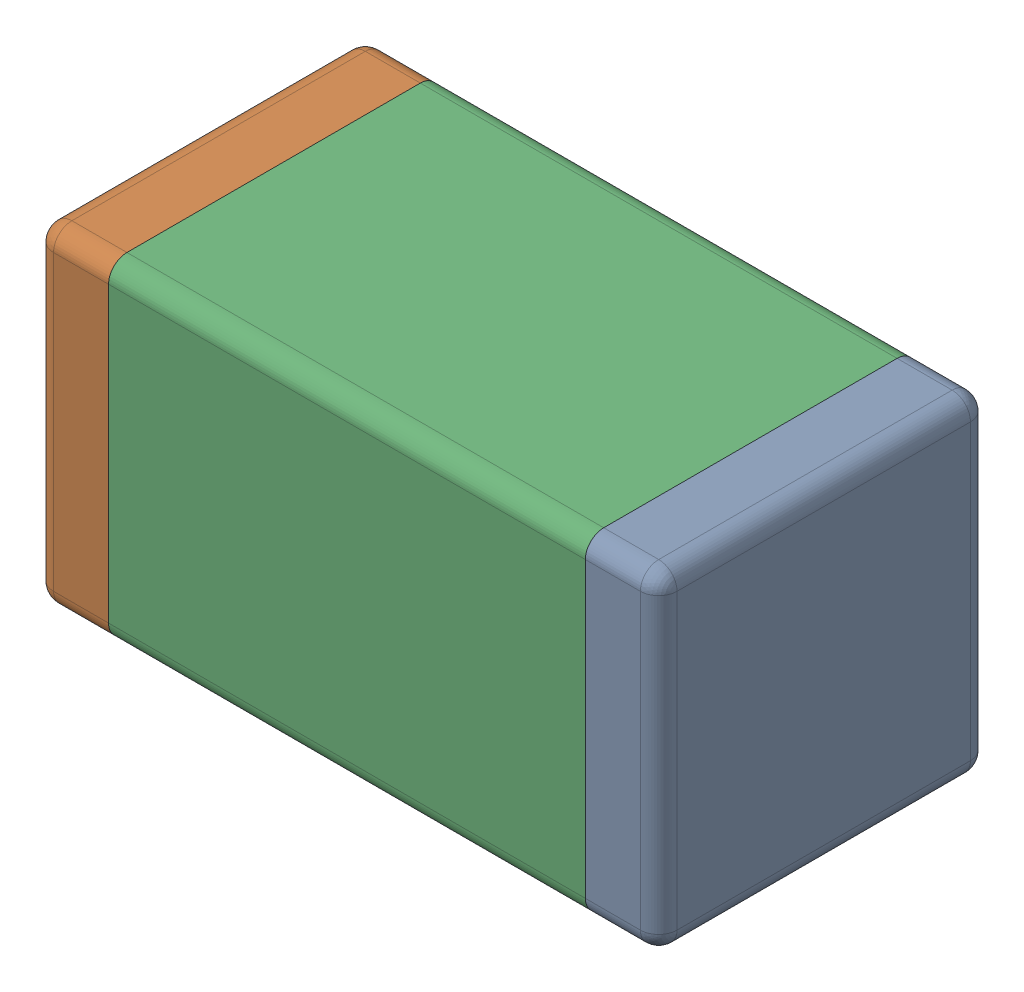
SolidWorks assembly C1, configuration Default. Lengths in mm.
Overall size (1.7 0.9 0.9).
6 component instances, 3 part files, 0 mates.
Components (placement in the parent):
- 6689447584-1: 6689447584 [Default] at (34.915 4.064 0) x (-1 0 0) z (0 0 1) size (1.7 0.9 0.9)
  - Terminal_6-1: Terminal_6 [Default] at (-0.85 -0.45 0) size (1.7 0.9 0.9)
    - Open CASCADE STEP translator 6.8 6.1.1_2-1: Open CASCADE STEP translator 6.8 6.1.1_2 [Default] at origin size (0.2 0.9 0.9)
    - Open CASCADE STEP translator 6.8 6.1.2_2-1: Open CASCADE STEP translator 6.8 6.1.2_2 [Default] at origin size (0.2 0.9 0.9)
  - Mid_Body_3-1: Mid_Body_3 [Default] at (-0.85 -0.45 0) size (1.3 0.9 0.9)
    - Open CASCADE STEP translator 6.8 6.2.1_2-1: Open CASCADE STEP translator 6.8 6.2.1_2 [Default] at origin size (1.3 0.9 0.9)
